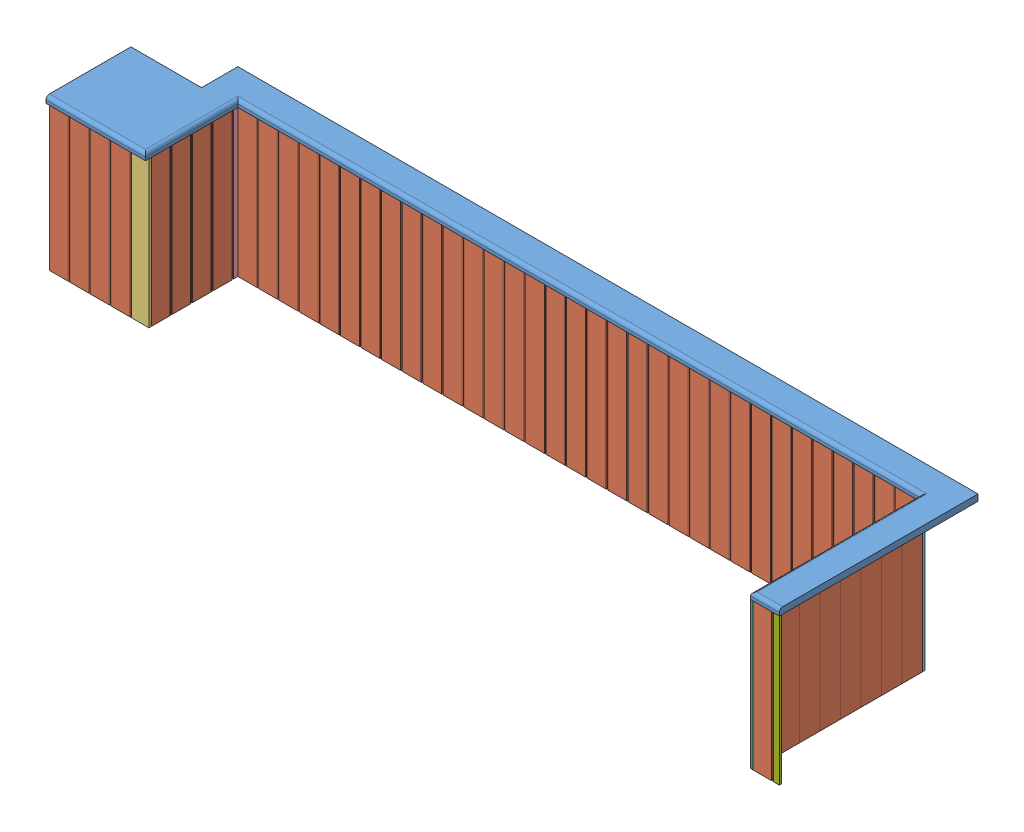
SolidWorks assembly Brüstung, configuration Standard. Lengths in mm.
Overall size (4870 900 1170).
56 component instances, 7 part files, 166 mates.
Components (placement in the parent):
- Platte-1: Platte [Standard] at (1989.1315 795.0064 4189) size (4774 38 1170)
- Wandbrett-1: Wandbrett [Standard] at (-2724.3685 795.0064 4876) x (1 0 0) z (0 0 -1) size (131 862 14)
- Wandbrett-2: Wandbrett [Standard] at (-2603.3685 795.0064 4876) x (1 0 0) z (0 0 -1) size (131 862 14)
- Wandbrett-3: Wandbrett [Standard] at (-2482.3685 795.0064 4876) x (1 0 0) z (0 0 -1) size (131 862 14)
- Wandbrett-4: Wandbrett [Standard] at (-2361.3685 795.0064 4876) x (1 0 0) z (0 0 -1) size (131 862 14)
- Wandbrett-Ecke1-1: Wandbrett-Ecke1 [Standard] at (-2240.3685 795.0064 4876) x (1 0 0) z (0 0 -1) size (102 862 14)
- Wandbrett-6: Wandbrett [Standard] at (-2205.8685 795.0064 4808.5) x (0 0 -1) z (-1 0 0) size (131 862 14)
- Wandbrett-7: Wandbrett [Standard] at (-2205.8685 795.0064 4687.5) x (0 0 -1) z (-1 0 0) size (131 862 14)
- Wandbrett-8: Wandbrett [Standard] at (-2205.8685 795.0064 4566.5) x (0 0 -1) z (-1 0 0) size (131 862 14)
- Wandbrett-9: Wandbrett [Standard] at (-2205.8685 795.0064 4445.5) x (0 0 -1) z (-1 0 0) size (131 862 14)
- Wandbrett-Ecke2-1: Wandbrett-Ecke2 [Standard] at (-2205.8685 795.0064 4324.5) x (0 0 -1) z (-1 0 0) size (60 862 14)
- Wandbrett-11: Wandbrett [Standard] at (-2138.3685 795.0064 4352) x (1 0 0) z (0 0 -1) size (131 862 14)
- Wandbrett-12: Wandbrett [Standard] at (-2017.3685 795.0064 4352) x (1 0 0) z (0 0 -1) size (131 862 14)
- Wandbrett-13: Wandbrett [Standard] at (-1896.3685 795.0064 4352) x (1 0 0) z (0 0 -1) size (131 862 14)
- Wandbrett-14: Wandbrett [Standard] at (-1775.3685 795.0064 4352) x (1 0 0) z (0 0 -1) size (131 862 14)
- Wandbrett-15: Wandbrett [Standard] at (-1654.3685 795.0064 4352) x (1 0 0) z (0 0 -1) size (131 862 14)
- Wandbrett-16: Wandbrett [Standard] at (-1533.3685 795.0064 4352) x (1 0 0) z (0 0 -1) size (131 862 14)
- Wandbrett-17: Wandbrett [Standard] at (-1412.3685 795.0064 4352) x (1 0 0) z (0 0 -1) size (131 862 14)
- Wandbrett-18: Wandbrett [Standard] at (-1291.3685 795.0064 4352) x (1 0 0) z (0 0 -1) size (131 862 14)
- Wandbrett-19: Wandbrett [Standard] at (-1170.3685 795.0064 4352) x (1 0 0) z (0 0 -1) size (131 862 14)
- Wandbrett-20: Wandbrett [Standard] at (-1049.3685 795.0064 4352) x (1 0 0) z (0 0 -1) size (131 862 14)
- Wandbrett-21: Wandbrett [Standard] at (-928.3685 795.0064 4352) x (1 0 0) z (0 0 -1) size (131 862 14)
- Wandbrett-22: Wandbrett [Standard] at (-807.3685 795.0064 4352) x (1 0 0) z (0 0 -1) size (131 862 14)
- Wandbrett-23: Wandbrett [Standard] at (-686.3685 795.0064 4352) x (1 0 0) z (0 0 -1) size (131 862 14)
- Wandbrett-24: Wandbrett [Standard] at (-565.3685 795.0064 4352) x (1 0 0) z (0 0 -1) size (131 862 14)
- Wandbrett-25: Wandbrett [Standard] at (-444.3685 795.0064 4352) x (1 0 0) z (0 0 -1) size (131 862 14)
- Wandbrett-26: Wandbrett [Standard] at (-323.3685 795.0064 4352) x (1 0 0) z (0 0 -1) size (131 862 14)
- Wandbrett-27: Wandbrett [Standard] at (-202.3685 795.0064 4352) x (1 0 0) z (0 0 -1) size (131 862 14)
- Wandbrett-28: Wandbrett [Standard] at (-81.3685 795.0064 4352) x (1 0 0) z (0 0 -1) size (131 862 14)
- Wandbrett-29: Wandbrett [Standard] at (39.6315 795.0064 4352) x (1 0 0) z (0 0 -1) size (131 862 14)
- Wandbrett-30: Wandbrett [Standard] at (160.6315 795.0064 4352) x (1 0 0) z (0 0 -1) size (131 862 14)
- Wandbrett-31: Wandbrett [Standard] at (281.6315 795.0064 4352) x (1 0 0) z (0 0 -1) size (131 862 14)
- Wandbrett-32: Wandbrett [Standard] at (402.6315 795.0064 4352) x (1 0 0) z (0 0 -1) size (131 862 14)
- Wandbrett-33: Wandbrett [Standard] at (523.6315 795.0064 4352) x (1 0 0) z (0 0 -1) size (131 862 14)
- Wandbrett-34: Wandbrett [Standard] at (644.6315 795.0064 4352) x (1 0 0) z (0 0 -1) size (131 862 14)
- Wandbrett-35: Wandbrett [Standard] at (765.6315 795.0064 4352) x (1 0 0) z (0 0 -1) size (131 862 14)
- Wandbrett-36: Wandbrett [Standard] at (886.6315 795.0064 4352) x (1 0 0) z (0 0 -1) size (131 862 14)
- Wandbrett-37: Wandbrett [Standard] at (1007.6315 795.0064 4352) x (1 0 0) z (0 0 -1) size (131 862 14)
- Wandbrett-38: Wandbrett [Standard] at (1128.6315 795.0064 4352) x (1 0 0) z (0 0 -1) size (131 862 14)
- Wandbrett-39: Wandbrett [Standard] at (1249.6315 795.0064 4352) x (1 0 0) z (0 0 -1) size (131 862 14)
- Wandbrett-40: Wandbrett [Standard] at (1370.6315 795.0064 4352) x (1 0 0) z (0 0 -1) size (131 862 14)
- Wandbrett-41: Wandbrett [Standard] at (1491.6315 795.0064 4352) x (1 0 0) z (0 0 -1) size (131 862 14)
- Wandbrett-42: Wandbrett [Standard] at (1612.6315 795.0064 4352) x (1 0 0) z (0 0 -1) size (131 862 14)
- Wandbrett-43: Wandbrett [Standard] at (1733.6315 795.0064 4352) x (1 0 0) z (0 0 -1) size (131 862 14)
- Wandbrett-Ecke3-1: Wandbrett-Ecke3 [Standard] at (1854.6315 795.0064 4352) x (1 0 0) z (0 0 -1) size (39 862 14)
- Wandbrett-44: Wandbrett [Standard] at (1826.1315 795.0064 4419.5) x (0 0 1) z (1 0 0) size (131 862 14)
- Wandbrett-45: Wandbrett [Standard] at (1826.1315 795.0064 4540.5) x (0 0 1) z (1 0 0) size (131 862 14)
- Wandbrett-46: Wandbrett [Standard] at (1826.1315 795.0064 4661.5) x (0 0 1) z (1 0 0) size (131 862 14)
- Wandbrett-47: Wandbrett [Standard] at (1826.1315 795.0064 4782.5) x (0 0 1) z (1 0 0) size (131 862 14)
- Wandbrett-48: Wandbrett [Standard] at (1826.1315 795.0064 4903.5) x (0 0 1) z (1 0 0) size (131 862 14)
- Wandbrett-49: Wandbrett [Standard] at (1826.1315 795.0064 5024.5) x (0 0 1) z (1 0 0) size (131 862 14)
- Wandbrett-50: Wandbrett [Standard] at (1826.1315 795.0064 5145.5) x (0 0 1) z (1 0 0) size (131 862 14)
- Wandbrett-51: Wandbrett [Standard] at (1826.1315 795.0064 5266.5) x (0 0 1) z (1 0 0) size (131 862 14)
- Wandbrett-Ecke4-1: Wandbrett-Ecke4 [Standard] at (1826.1315 795.0064 5387.5) x (0 0 1) z (1 0 0) size (32 862 14)
- Wandbrett-52: Wandbrett [Standard] at (1893.6315 795.0064 5352) x (1 0 0) z (0 0 -1) size (131 862 14)
- Wandbrett-Ecke5-1: Wandbrett-Ecke5 [Standard] at (2014.6315 795.0064 5352) x (1 0 0) z (0 0 -1) size (131 862 14)
Mates (geometry in assembly coordinates):
- Deckungsgleich1: coincident anti-aligned: plane of Platte-1 through (1989.1315 795.0064 4189) normal (0 -1 0); plane of Wandbrett-1 through (-2674.8685 795.0064 4879) normal (0 1 0)
- Deckungsgleich2: coincident anti-aligned: plane of Platte-1 through (1989.1315 795.0064 4189) normal (0 -1 0); plane of Wandbrett-2 through (-2553.8685 795.0064 4879) normal (0 1 0)
- Deckungsgleich3: coincident anti-aligned: plane of Platte-1 through (1989.1315 795.0064 4189) normal (0 -1 0); plane of Wandbrett-3 through (-2432.8685 795.0064 4879) normal (0 1 0)
- Deckungsgleich4: coincident anti-aligned: plane of Platte-1 through (1989.1315 795.0064 4189) normal (0 -1 0); plane of Wandbrett-4 through (-2311.8685 795.0064 4879) normal (0 1 0)
- Parallel1: parallel aligned: plane of Platte-1 through (-2784.8685 833.0064 4903) normal (0 0 1); plane of Wandbrett-1 through (-2674.8685 -66.9936 4883) normal (0 0 1)
- Abstand2: distance = 20 mm aligned: plane of Wandbrett-1 through (-2674.8685 -66.9936 4883) normal (0 0 1); plane of Platte-1 through (-2784.8685 833.0064 4903) normal (0 0 1)
- Deckungsgleich9: coincident aligned: plane of Platte-1 through (-2784.8685 833.0064 4903) normal (-1 0 0); plane of Wandbrett-1 through (-2784.8685 -66.9936 4869) normal (-1 0 0)
- Deckungsgleich10: coincident anti-aligned: plane of Wandbrett-1 through (-2663.8685 -66.9936 4878) normal (0 0 1); plane of Wandbrett-2 through (-2653.8685 -66.9936 4878) normal (0 0 -1)
- Deckungsgleich11: coincident anti-aligned: plane of Wandbrett-2 through (-2542.8685 -66.9936 4878) normal (0 0 1); plane of Wandbrett-3 through (-2532.8685 -66.9936 4878) normal (0 0 -1)
- Deckungsgleich12: coincident anti-aligned: plane of Wandbrett-3 through (-2421.8685 -66.9936 4878) normal (0 0 1); plane of Wandbrett-4 through (-2411.8685 -66.9936 4878) normal (0 0 -1)
- Deckungsgleich14: coincident anti-aligned: plane of Wandbrett-1 through (-2653.8685 -66.9936 4878) normal (1 0 0); plane of Wandbrett-2 through (-2653.8685 -66.9936 4874) normal (-1 0 0)
- Deckungsgleich15: coincident anti-aligned: plane of Wandbrett-2 through (-2532.8685 -66.9936 4878) normal (1 0 0); plane of Wandbrett-3 through (-2532.8685 -66.9936 4874) normal (-1 0 0)
- Deckungsgleich16: coincident anti-aligned: plane of Wandbrett-3 through (-2411.8685 -66.9936 4878) normal (1 0 0); plane of Wandbrett-4 through (-2411.8685 -66.9936 4874) normal (-1 0 0)
- Deckungsgleich18: coincident anti-aligned: plane of Platte-1 through (1989.1315 795.0064 4189) normal (0 -1 0); plane of Wandbrett-Ecke1-1 through (-2190.8685 795.0064 4879) normal (0 1 0)
- Deckungsgleich19: coincident anti-aligned: plane of Wandbrett-4 through (-2300.8685 -66.9936 4878) normal (0 0 1); plane of Wandbrett-Ecke1-1 through (-2290.8685 -66.9936 4878) normal (0 0 -1)
- Deckungsgleich20: coincident anti-aligned: plane of Wandbrett-4 through (-2290.8685 -66.9936 4878) normal (1 0 0); plane of Wandbrett-Ecke1-1 through (-2290.8685 -66.9936 4874) normal (-1 0 0)
- Deckungsgleich21: coincident anti-aligned: plane of Platte-1 through (1989.1315 795.0064 4189) normal (0 -1 0); plane of Wandbrett-6 through (-2202.8685 795.0064 4759) normal (0 1 0)
- Deckungsgleich22: coincident anti-aligned: plane of Platte-1 through (1989.1315 795.0064 4189) normal (0 -1 0); plane of Wandbrett-7 through (-2202.8685 795.0064 4638) normal (0 1 0)
- Deckungsgleich23: coincident anti-aligned: plane of Platte-1 through (1989.1315 795.0064 4189) normal (0 -1 0); plane of Wandbrett-8 through (-2202.8685 795.0064 4517) normal (0 1 0)
- Deckungsgleich24: coincident anti-aligned: plane of Platte-1 through (1989.1315 795.0064 4189) normal (0 -1 0); plane of Wandbrett-9 through (-2202.8685 795.0064 4396) normal (0 1 0)
- Deckungsgleich26: coincident anti-aligned: plane of Wandbrett-Ecke1-1 through (-2179.8685 -66.9936 4869) normal (0 0 -1); plane of Wandbrett-6 through (-2212.8685 -66.9936 4869) normal (0 0 1)
- Deckungsgleich27: coincident aligned: plane of Platte-1 through (-2198.8685 833.0064 4359) normal (1 0 0); plane of Wandbrett-6 through (-2198.8685 -66.9936 4759) normal (1 0 0)
- Deckungsgleich28: coincident anti-aligned: plane of Wandbrett-6 through (-2203.8685 -66.9936 4748) normal (1 0 0); plane of Wandbrett-7 through (-2203.8685 -66.9936 4738) normal (-1 0 0)
- Deckungsgleich29: coincident anti-aligned: plane of Wandbrett-7 through (-2203.8685 -66.9936 4627) normal (1 0 0); plane of Wandbrett-8 through (-2203.8685 -66.9936 4617) normal (-1 0 0)
- Deckungsgleich30: coincident anti-aligned: plane of Wandbrett-8 through (-2203.8685 -66.9936 4506) normal (1 0 0); plane of Wandbrett-9 through (-2203.8685 -66.9936 4496) normal (-1 0 0)
- Deckungsgleich32: coincident anti-aligned: plane of Wandbrett-6 through (-2203.8685 -66.9936 4738) normal (0 0 -1); plane of Wandbrett-7 through (-2207.8685 -66.9936 4738) normal (0 0 1)
- Deckungsgleich33: coincident anti-aligned: plane of Wandbrett-7 through (-2203.8685 -66.9936 4617) normal (0 0 -1); plane of Wandbrett-8 through (-2207.8685 -66.9936 4617) normal (0 0 1)
- Deckungsgleich34: coincident anti-aligned: plane of Wandbrett-8 through (-2203.8685 -66.9936 4496) normal (0 0 -1); plane of Wandbrett-9 through (-2207.8685 -66.9936 4496) normal (0 0 1)
- Deckungsgleich36: coincident anti-aligned: plane of Platte-1 through (1989.1315 795.0064 4189) normal (0 -1 0); plane of Wandbrett-Ecke2-1 through (-2202.8685 795.0064 4275) normal (0 1 0)
- Deckungsgleich37: coincident anti-aligned: plane of Wandbrett-9 through (-2203.8685 -66.9936 4385) normal (1 0 0); plane of Wandbrett-Ecke2-1 through (-2203.8685 -66.9936 4375) normal (-1 0 0)
- Deckungsgleich38: coincident anti-aligned: plane of Wandbrett-9 through (-2203.8685 -66.9936 4375) normal (0 0 -1); plane of Wandbrett-Ecke2-1 through (-2207.8685 -66.9936 4375) normal (0 0 1)
- Deckungsgleich39: coincident anti-aligned: plane of Platte-1 through (1989.1315 795.0064 4189) normal (0 -1 0); plane of Wandbrett-11 through (-2088.8685 795.0064 4355) normal (0 1 0)
- Deckungsgleich40: coincident anti-aligned: plane of Platte-1 through (1989.1315 795.0064 4189) normal (0 -1 0); plane of Wandbrett-12 through (-1967.8685 795.0064 4355) normal (0 1 0)
- Deckungsgleich41: coincident anti-aligned: plane of Platte-1 through (1989.1315 795.0064 4189) normal (0 -1 0); plane of Wandbrett-13 through (-1846.8685 795.0064 4355) normal (0 1 0)
- Deckungsgleich42: coincident anti-aligned: plane of Platte-1 through (1989.1315 795.0064 4189) normal (0 -1 0); plane of Wandbrett-14 through (-1725.8685 795.0064 4355) normal (0 1 0)
- Deckungsgleich43: coincident anti-aligned: plane of Platte-1 through (1989.1315 795.0064 4189) normal (0 -1 0); plane of Wandbrett-15 through (-1604.8685 795.0064 4355) normal (0 1 0)
- Deckungsgleich44: coincident anti-aligned: plane of Platte-1 through (1989.1315 795.0064 4189) normal (0 -1 0); plane of Wandbrett-16 through (-1483.8685 795.0064 4355) normal (0 1 0)
- Deckungsgleich45: coincident anti-aligned: plane of Platte-1 through (1989.1315 795.0064 4189) normal (0 -1 0); plane of Wandbrett-17 through (-1362.8685 795.0064 4355) normal (0 1 0)
- Deckungsgleich46: coincident anti-aligned: plane of Platte-1 through (1989.1315 795.0064 4189) normal (0 -1 0); plane of Wandbrett-18 through (-1241.8685 795.0064 4355) normal (0 1 0)
- Deckungsgleich47: coincident anti-aligned: plane of Platte-1 through (1989.1315 795.0064 4189) normal (0 -1 0); plane of Wandbrett-19 through (-1120.8685 795.0064 4355) normal (0 1 0)
- Deckungsgleich48: coincident anti-aligned: plane of Platte-1 through (1989.1315 795.0064 4189) normal (0 -1 0); plane of Wandbrett-20 through (-999.8685 795.0064 4355) normal (0 1 0)
- Deckungsgleich49: coincident anti-aligned: plane of Platte-1 through (1989.1315 795.0064 4189) normal (0 -1 0); plane of Wandbrett-21 through (-878.8685 795.0064 4355) normal (0 1 0)
- Deckungsgleich50: coincident anti-aligned: plane of Platte-1 through (1989.1315 795.0064 4189) normal (0 -1 0); plane of Wandbrett-22 through (-757.8685 795.0064 4355) normal (0 1 0)
- Deckungsgleich51: coincident anti-aligned: plane of Platte-1 through (1989.1315 795.0064 4189) normal (0 -1 0); plane of Wandbrett-23 through (-636.8685 795.0064 4355) normal (0 1 0)
- Deckungsgleich52: coincident anti-aligned: plane of Platte-1 through (1989.1315 795.0064 4189) normal (0 -1 0); plane of Wandbrett-24 through (-515.8685 795.0064 4355) normal (0 1 0)
- Deckungsgleich53: coincident anti-aligned: plane of Platte-1 through (1989.1315 795.0064 4189) normal (0 -1 0); plane of Wandbrett-25 through (-394.8685 795.0064 4355) normal (0 1 0)
- Deckungsgleich54: coincident anti-aligned: plane of Platte-1 through (1989.1315 795.0064 4189) normal (0 -1 0); plane of Wandbrett-26 through (-273.8685 795.0064 4355) normal (0 1 0)
- Deckungsgleich55: coincident anti-aligned: plane of Platte-1 through (1989.1315 795.0064 4189) normal (0 -1 0); plane of Wandbrett-27 through (-152.8685 795.0064 4355) normal (0 1 0)
- Deckungsgleich56: coincident anti-aligned: plane of Platte-1 through (1989.1315 795.0064 4189) normal (0 -1 0); plane of Wandbrett-28 through (-31.8685 795.0064 4355) normal (0 1 0)
- Deckungsgleich57: coincident anti-aligned: plane of Platte-1 through (1989.1315 795.0064 4189) normal (0 -1 0); plane of Wandbrett-29 through (89.1315 795.0064 4355) normal (0 1 0)
- Deckungsgleich58: coincident anti-aligned: plane of Platte-1 through (1989.1315 795.0064 4189) normal (0 -1 0); plane of Wandbrett-30 through (210.1315 795.0064 4355) normal (0 1 0)
- Deckungsgleich59: coincident anti-aligned: plane of Platte-1 through (1989.1315 795.0064 4189) normal (0 -1 0); plane of Wandbrett-31 through (331.1315 795.0064 4355) normal (0 1 0)
- Deckungsgleich60: coincident anti-aligned: plane of Platte-1 through (1989.1315 795.0064 4189) normal (0 -1 0); plane of Wandbrett-32 through (452.1315 795.0064 4355) normal (0 1 0)
- Deckungsgleich61: coincident anti-aligned: plane of Platte-1 through (1989.1315 795.0064 4189) normal (0 -1 0); plane of Wandbrett-33 through (573.1315 795.0064 4355) normal (0 1 0)
- Deckungsgleich62: coincident anti-aligned: plane of Platte-1 through (1989.1315 795.0064 4189) normal (0 -1 0); plane of Wandbrett-34 through (694.1315 795.0064 4355) normal (0 1 0)
- Deckungsgleich63: coincident anti-aligned: plane of Platte-1 through (1989.1315 795.0064 4189) normal (0 -1 0); plane of Wandbrett-35 through (815.1315 795.0064 4355) normal (0 1 0)
- Deckungsgleich64: coincident anti-aligned: plane of Platte-1 through (1989.1315 795.0064 4189) normal (0 -1 0); plane of Wandbrett-36 through (936.1315 795.0064 4355) normal (0 1 0)
- Deckungsgleich65: coincident anti-aligned: plane of Platte-1 through (1989.1315 795.0064 4189) normal (0 -1 0); plane of Wandbrett-37 through (1057.1315 795.0064 4355) normal (0 1 0)
- Deckungsgleich66: coincident anti-aligned: plane of Platte-1 through (1989.1315 795.0064 4189) normal (0 -1 0); plane of Wandbrett-38 through (1178.1315 795.0064 4355) normal (0 1 0)
- Deckungsgleich67: coincident anti-aligned: plane of Platte-1 through (1989.1315 795.0064 4189) normal (0 -1 0); plane of Wandbrett-39 through (1299.1315 795.0064 4355) normal (0 1 0)
- Deckungsgleich68: coincident anti-aligned: plane of Platte-1 through (1989.1315 795.0064 4189) normal (0 -1 0); plane of Wandbrett-40 through (1420.1315 795.0064 4355) normal (0 1 0)
- Deckungsgleich69: coincident anti-aligned: plane of Platte-1 through (1989.1315 795.0064 4189) normal (0 -1 0); plane of Wandbrett-41 through (1541.1315 795.0064 4355) normal (0 1 0)
- Deckungsgleich70: coincident anti-aligned: plane of Platte-1 through (1989.1315 795.0064 4189) normal (0 -1 0); plane of Wandbrett-42 through (1662.1315 795.0064 4355) normal (0 1 0)
- Deckungsgleich71: coincident anti-aligned: plane of Wandbrett-Ecke2-1 through (-2198.8685 -66.9936 4275) normal (1 0 0); plane of Wandbrett-11 through (-2198.8685 -66.9936 4354) normal (-1 0 0)
- Deckungsgleich72: coincident anti-aligned: plane of Wandbrett-11 through (-2077.8685 -66.9936 4354) normal (0 0 1); plane of Wandbrett-12 through (-2067.8685 -66.9936 4354) normal (0 0 -1)
- Deckungsgleich73: coincident anti-aligned: plane of Wandbrett-12 through (-1956.8685 -66.9936 4354) normal (0 0 1); plane of Wandbrett-13 through (-1946.8685 -66.9936 4354) normal (0 0 -1)
- Deckungsgleich74: coincident anti-aligned: plane of Wandbrett-13 through (-1835.8685 -66.9936 4354) normal (0 0 1); plane of Wandbrett-14 through (-1825.8685 -66.9936 4354) normal (0 0 -1)
- Deckungsgleich75: coincident anti-aligned: plane of Wandbrett-14 through (-1714.8685 -66.9936 4354) normal (0 0 1); plane of Wandbrett-15 through (-1704.8685 -66.9936 4354) normal (0 0 -1)
- Deckungsgleich76: coincident anti-aligned: plane of Wandbrett-15 through (-1593.8685 -66.9936 4354) normal (0 0 1); plane of Wandbrett-16 through (-1583.8685 -66.9936 4354) normal (0 0 -1)
- Deckungsgleich77: coincident anti-aligned: plane of Wandbrett-16 through (-1472.8685 -66.9936 4354) normal (0 0 1); plane of Wandbrett-17 through (-1462.8685 -66.9936 4354) normal (0 0 -1)
- Deckungsgleich78: coincident anti-aligned: plane of Wandbrett-17 through (-1351.8685 -66.9936 4354) normal (0 0 1); plane of Wandbrett-18 through (-1341.8685 -66.9936 4354) normal (0 0 -1)
- Deckungsgleich79: coincident anti-aligned: plane of Wandbrett-18 through (-1230.8685 -66.9936 4354) normal (0 0 1); plane of Wandbrett-19 through (-1220.8685 -66.9936 4354) normal (0 0 -1)
- Deckungsgleich80: coincident anti-aligned: plane of Wandbrett-19 through (-1109.8685 -66.9936 4354) normal (0 0 1); plane of Wandbrett-20 through (-1099.8685 -66.9936 4354) normal (0 0 -1)
- Deckungsgleich81: coincident anti-aligned: plane of Wandbrett-20 through (-988.8685 -66.9936 4354) normal (0 0 1); plane of Wandbrett-21 through (-978.8685 -66.9936 4354) normal (0 0 -1)
- Deckungsgleich82: coincident anti-aligned: plane of Wandbrett-21 through (-867.8685 -66.9936 4354) normal (0 0 1); plane of Wandbrett-22 through (-857.8685 -66.9936 4354) normal (0 0 -1)
- Deckungsgleich83: coincident anti-aligned: plane of Wandbrett-22 through (-746.8685 -66.9936 4354) normal (0 0 1); plane of Wandbrett-23 through (-736.8685 -66.9936 4354) normal (0 0 -1)
- Deckungsgleich84: coincident anti-aligned: plane of Wandbrett-23 through (-625.8685 -66.9936 4354) normal (0 0 1); plane of Wandbrett-24 through (-615.8685 -66.9936 4354) normal (0 0 -1)
- Deckungsgleich85: coincident anti-aligned: plane of Wandbrett-24 through (-504.8685 -66.9936 4354) normal (0 0 1); plane of Wandbrett-25 through (-494.8685 -66.9936 4354) normal (0 0 -1)
- Deckungsgleich86: coincident anti-aligned: plane of Wandbrett-25 through (-383.8685 -66.9936 4354) normal (0 0 1); plane of Wandbrett-26 through (-373.8685 -66.9936 4354) normal (0 0 -1)
- Deckungsgleich87: coincident anti-aligned: plane of Wandbrett-26 through (-262.8685 -66.9936 4354) normal (0 0 1); plane of Wandbrett-27 through (-252.8685 -66.9936 4354) normal (0 0 -1)
- Deckungsgleich88: coincident anti-aligned: plane of Wandbrett-27 through (-141.8685 -66.9936 4354) normal (0 0 1); plane of Wandbrett-28 through (-131.8685 -66.9936 4354) normal (0 0 -1)
- Deckungsgleich90: coincident anti-aligned: plane of Wandbrett-28 through (-20.8685 -66.9936 4354) normal (0 0 1); plane of Wandbrett-29 through (-10.8685 -66.9936 4354) normal (0 0 -1)
- Deckungsgleich91: coincident anti-aligned: plane of Wandbrett-29 through (100.1315 -66.9936 4354) normal (0 0 1); plane of Wandbrett-30 through (110.1315 -66.9936 4354) normal (0 0 -1)
- Deckungsgleich92: coincident anti-aligned: plane of Wandbrett-30 through (221.1315 -66.9936 4354) normal (0 0 1); plane of Wandbrett-31 through (231.1315 -66.9936 4354) normal (0 0 -1)
- Deckungsgleich93: coincident anti-aligned: plane of Wandbrett-31 through (342.1315 -66.9936 4354) normal (0 0 1); plane of Wandbrett-32 through (352.1315 -66.9936 4354) normal (0 0 -1)
- Deckungsgleich94: coincident anti-aligned: plane of Wandbrett-32 through (463.1315 -66.9936 4354) normal (0 0 1); plane of Wandbrett-33 through (473.1315 -66.9936 4354) normal (0 0 -1)
- Deckungsgleich95: coincident anti-aligned: plane of Wandbrett-33 through (584.1315 -66.9936 4354) normal (0 0 1); plane of Wandbrett-34 through (594.1315 -66.9936 4354) normal (0 0 -1)
- Deckungsgleich96: coincident anti-aligned: plane of Wandbrett-34 through (705.1315 -66.9936 4354) normal (0 0 1); plane of Wandbrett-35 through (715.1315 -66.9936 4354) normal (0 0 -1)
- Deckungsgleich97: coincident anti-aligned: plane of Wandbrett-35 through (826.1315 -66.9936 4354) normal (0 0 1); plane of Wandbrett-36 through (836.1315 -66.9936 4354) normal (0 0 -1)
- Deckungsgleich98: coincident anti-aligned: plane of Wandbrett-36 through (947.1315 -66.9936 4354) normal (0 0 1); plane of Wandbrett-37 through (957.1315 -66.9936 4354) normal (0 0 -1)
- Deckungsgleich99: coincident anti-aligned: plane of Wandbrett-37 through (1068.1315 -66.9936 4354) normal (0 0 1); plane of Wandbrett-38 through (1078.1315 -66.9936 4354) normal (0 0 -1)
- Deckungsgleich100: coincident anti-aligned: plane of Wandbrett-38 through (1189.1315 -66.9936 4354) normal (0 0 1); plane of Wandbrett-39 through (1199.1315 -66.9936 4354) normal (0 0 -1)
- Deckungsgleich101: coincident anti-aligned: plane of Wandbrett-39 through (1310.1315 -66.9936 4354) normal (0 0 1); plane of Wandbrett-40 through (1320.1315 -66.9936 4354) normal (0 0 -1)
- Deckungsgleich102: coincident anti-aligned: plane of Wandbrett-40 through (1431.1315 -66.9936 4354) normal (0 0 1); plane of Wandbrett-41 through (1441.1315 -66.9936 4354) normal (0 0 -1)
- Deckungsgleich103: coincident anti-aligned: plane of Wandbrett-41 through (1552.1315 -66.9936 4354) normal (0 0 1); plane of Wandbrett-42 through (1562.1315 -66.9936 4354) normal (0 0 -1)
- Deckungsgleich104: coincident aligned: plane of Platte-1 through (-2198.8685 833.0064 4359) normal (0 0 1); plane of Wandbrett-11 through (-2088.8685 -66.9936 4359) normal (0 0 1)
- Deckungsgleich105: coincident anti-aligned: plane of Wandbrett-11 through (-2067.8685 -66.9936 4354) normal (1 0 0); plane of Wandbrett-12 through (-2067.8685 -66.9936 4350) normal (-1 0 0)
- Deckungsgleich106: coincident anti-aligned: plane of Wandbrett-12 through (-1946.8685 -66.9936 4354) normal (1 0 0); plane of Wandbrett-13 through (-1946.8685 -66.9936 4350) normal (-1 0 0)
- Deckungsgleich107: coincident anti-aligned: plane of Wandbrett-13 through (-1825.8685 -66.9936 4354) normal (1 0 0); plane of Wandbrett-14 through (-1825.8685 -66.9936 4350) normal (-1 0 0)
- Deckungsgleich108: coincident anti-aligned: plane of Wandbrett-14 through (-1704.8685 -66.9936 4354) normal (1 0 0); plane of Wandbrett-15 through (-1704.8685 -66.9936 4350) normal (-1 0 0)
- Deckungsgleich109: coincident anti-aligned: plane of Wandbrett-15 through (-1583.8685 -66.9936 4354) normal (1 0 0); plane of Wandbrett-16 through (-1583.8685 -66.9936 4350) normal (-1 0 0)
- Deckungsgleich110: coincident anti-aligned: plane of Wandbrett-16 through (-1462.8685 -66.9936 4354) normal (1 0 0); plane of Wandbrett-17 through (-1462.8685 -66.9936 4350) normal (-1 0 0)
- Deckungsgleich111: coincident anti-aligned: plane of Wandbrett-17 through (-1341.8685 -66.9936 4354) normal (1 0 0); plane of Wandbrett-18 through (-1341.8685 -66.9936 4350) normal (-1 0 0)
- Deckungsgleich112: coincident anti-aligned: plane of Wandbrett-18 through (-1220.8685 -66.9936 4354) normal (1 0 0); plane of Wandbrett-19 through (-1220.8685 -66.9936 4350) normal (-1 0 0)
- Deckungsgleich113: coincident anti-aligned: plane of Wandbrett-19 through (-1099.8685 -66.9936 4354) normal (1 0 0); plane of Wandbrett-20 through (-1099.8685 -66.9936 4350) normal (-1 0 0)
- Deckungsgleich114: coincident anti-aligned: plane of Wandbrett-20 through (-978.8685 -66.9936 4354) normal (1 0 0); plane of Wandbrett-21 through (-978.8685 -66.9936 4350) normal (-1 0 0)
- Deckungsgleich115: coincident anti-aligned: plane of Wandbrett-21 through (-857.8685 -66.9936 4354) normal (1 0 0); plane of Wandbrett-22 through (-857.8685 -66.9936 4350) normal (-1 0 0)
- Deckungsgleich117: coincident anti-aligned: plane of Wandbrett-22 through (-736.8685 -66.9936 4354) normal (1 0 0); plane of Wandbrett-23 through (-736.8685 -66.9936 4350) normal (-1 0 0)
- Deckungsgleich118: coincident anti-aligned: plane of Wandbrett-23 through (-615.8685 -66.9936 4354) normal (1 0 0); plane of Wandbrett-24 through (-615.8685 -66.9936 4350) normal (-1 0 0)
- Deckungsgleich119: coincident anti-aligned: plane of Wandbrett-24 through (-494.8685 -66.9936 4354) normal (1 0 0); plane of Wandbrett-25 through (-494.8685 -66.9936 4350) normal (-1 0 0)
- Deckungsgleich121: coincident anti-aligned: plane of Wandbrett-25 through (-373.8685 -66.9936 4354) normal (1 0 0); plane of Wandbrett-26 through (-373.8685 -66.9936 4350) normal (-1 0 0)
- Deckungsgleich122: coincident anti-aligned: plane of Wandbrett-26 through (-252.8685 -66.9936 4354) normal (1 0 0); plane of Wandbrett-27 through (-252.8685 -66.9936 4350) normal (-1 0 0)
- Deckungsgleich123: coincident anti-aligned: plane of Wandbrett-27 through (-131.8685 -66.9936 4354) normal (1 0 0); plane of Wandbrett-28 through (-131.8685 -66.9936 4350) normal (-1 0 0)
- Deckungsgleich124: coincident anti-aligned: plane of Wandbrett-28 through (-10.8685 -66.9936 4354) normal (1 0 0); plane of Wandbrett-29 through (-10.8685 -66.9936 4350) normal (-1 0 0)
- Deckungsgleich125: coincident anti-aligned: plane of Wandbrett-29 through (110.1315 -66.9936 4354) normal (1 0 0); plane of Wandbrett-30 through (110.1315 -66.9936 4350) normal (-1 0 0)
- Deckungsgleich126: coincident anti-aligned: plane of Wandbrett-30 through (231.1315 -66.9936 4354) normal (1 0 0); plane of Wandbrett-31 through (231.1315 -66.9936 4350) normal (-1 0 0)
- Deckungsgleich127: coincident anti-aligned: plane of Wandbrett-31 through (352.1315 -66.9936 4354) normal (1 0 0); plane of Wandbrett-32 through (352.1315 -66.9936 4350) normal (-1 0 0)
- Deckungsgleich128: coincident anti-aligned: plane of Wandbrett-32 through (473.1315 -66.9936 4354) normal (1 0 0); plane of Wandbrett-33 through (473.1315 -66.9936 4350) normal (-1 0 0)
- Deckungsgleich129: coincident anti-aligned: plane of Wandbrett-33 through (594.1315 -66.9936 4354) normal (1 0 0); plane of Wandbrett-34 through (594.1315 -66.9936 4350) normal (-1 0 0)
- Deckungsgleich130: coincident anti-aligned: plane of Wandbrett-34 through (715.1315 -66.9936 4354) normal (1 0 0); plane of Wandbrett-35 through (715.1315 -66.9936 4350) normal (-1 0 0)
- Deckungsgleich131: coincident anti-aligned: plane of Wandbrett-35 through (836.1315 -66.9936 4354) normal (1 0 0); plane of Wandbrett-36 through (836.1315 -66.9936 4350) normal (-1 0 0)
- Deckungsgleich132: coincident anti-aligned: plane of Wandbrett-36 through (957.1315 -66.9936 4354) normal (1 0 0); plane of Wandbrett-37 through (957.1315 -66.9936 4350) normal (-1 0 0)
- Deckungsgleich133: coincident anti-aligned: plane of Wandbrett-37 through (1078.1315 -66.9936 4354) normal (1 0 0); plane of Wandbrett-38 through (1078.1315 -66.9936 4350) normal (-1 0 0)
- Deckungsgleich136: coincident anti-aligned: plane of Wandbrett-38 through (1199.1315 -66.9936 4354) normal (1 0 0); plane of Wandbrett-39 through (1199.1315 -66.9936 4350) normal (-1 0 0)
- Deckungsgleich137: coincident anti-aligned: plane of Wandbrett-39 through (1320.1315 -66.9936 4354) normal (1 0 0); plane of Wandbrett-40 through (1320.1315 -66.9936 4350) normal (-1 0 0)
- Deckungsgleich138: coincident anti-aligned: plane of Wandbrett-40 through (1441.1315 -66.9936 4354) normal (1 0 0); plane of Wandbrett-41 through (1441.1315 -66.9936 4350) normal (-1 0 0)
- Deckungsgleich139: coincident anti-aligned: plane of Wandbrett-41 through (1562.1315 -66.9936 4354) normal (1 0 0); plane of Wandbrett-42 through (1562.1315 -66.9936 4350) normal (-1 0 0)
- Deckungsgleich140: coincident anti-aligned: plane of Platte-1 through (1989.1315 795.0064 4189) normal (0 -1 0); plane of Wandbrett-43 through (1783.1315 795.0064 4355) normal (0 1 0)
- Deckungsgleich141: coincident anti-aligned: plane of Wandbrett-42 through (1673.1315 -66.9936 4354) normal (0 0 1); plane of Wandbrett-43 through (1683.1315 -66.9936 4354) normal (0 0 -1)
- Deckungsgleich142: coincident anti-aligned: plane of Wandbrett-42 through (1683.1315 -66.9936 4354) normal (1 0 0); plane of Wandbrett-43 through (1683.1315 -66.9936 4350) normal (-1 0 0)
- Deckungsgleich143: coincident anti-aligned: plane of Platte-1 through (1989.1315 795.0064 4189) normal (0 -1 0); plane of Wandbrett-Ecke3-1 through (1904.1315 795.0064 4355) normal (0 1 0)
- Deckungsgleich144: coincident anti-aligned: plane of Wandbrett-43 through (1794.1315 -66.9936 4354) normal (0 0 1); plane of Wandbrett-Ecke3-1 through (1804.1315 -66.9936 4354) normal (0 0 -1)
- Deckungsgleich145: coincident anti-aligned: plane of Wandbrett-43 through (1804.1315 -66.9936 4354) normal (1 0 0); plane of Wandbrett-Ecke3-1 through (1804.1315 -66.9936 4350) normal (-1 0 0)
- Deckungsgleich156: coincident anti-aligned: plane of Platte-1 through (1989.1315 795.0064 4189) normal (0 -1 0); plane of Wandbrett-44 through (1823.1315 795.0064 4469) normal (0 1 0)
- Deckungsgleich157: coincident anti-aligned: plane of Platte-1 through (1989.1315 795.0064 4189) normal (0 -1 0); plane of Wandbrett-45 through (1823.1315 795.0064 4590) normal (0 1 0)
- Deckungsgleich158: coincident anti-aligned: plane of Platte-1 through (1989.1315 795.0064 4189) normal (0 -1 0); plane of Wandbrett-46 through (1823.1315 795.0064 4711) normal (0 1 0)
- Deckungsgleich159: coincident anti-aligned: plane of Platte-1 through (1989.1315 795.0064 4189) normal (0 -1 0); plane of Wandbrett-47 through (1823.1315 795.0064 4832) normal (0 1 0)
- Deckungsgleich160: coincident anti-aligned: plane of Platte-1 through (1989.1315 795.0064 4189) normal (0 -1 0); plane of Wandbrett-48 through (1823.1315 795.0064 4953) normal (0 1 0)
- Deckungsgleich161: coincident anti-aligned: plane of Platte-1 through (1989.1315 795.0064 4189) normal (0 -1 0); plane of Wandbrett-49 through (1823.1315 795.0064 5074) normal (0 1 0)
- Deckungsgleich162: coincident anti-aligned: plane of Platte-1 through (1989.1315 795.0064 4189) normal (0 -1 0); plane of Wandbrett-50 through (1823.1315 795.0064 5195) normal (0 1 0)
- Deckungsgleich163: coincident anti-aligned: plane of Platte-1 through (1989.1315 795.0064 4189) normal (0 -1 0); plane of Wandbrett-51 through (1823.1315 795.0064 5316) normal (0 1 0)
- Deckungsgleich164: coincident anti-aligned: plane of Wandbrett-Ecke3-1 through (1904.1315 -66.9936 4359) normal (0 0 1); plane of Wandbrett-44 through (1824.1315 -66.9936 4359) normal (0 0 -1)
- Deckungsgleich165: coincident aligned: plane of Platte-1 through (1819.1315 833.0064 4359) normal (-1 0 0); plane of Wandbrett-44 through (1819.1315 -66.9936 4469) normal (-1 0 0)
- Deckungsgleich166: coincident anti-aligned: plane of Wandbrett-44 through (1824.1315 -66.9936 4480) normal (-1 0 0); plane of Wandbrett-45 through (1824.1315 -66.9936 4490) normal (1 0 0)
- Deckungsgleich167: coincident anti-aligned: plane of Wandbrett-45 through (1824.1315 -66.9936 4601) normal (-1 0 0); plane of Wandbrett-46 through (1824.1315 -66.9936 4611) normal (1 0 0)
- Deckungsgleich168: coincident anti-aligned: plane of Wandbrett-46 through (1824.1315 -66.9936 4722) normal (-1 0 0); plane of Wandbrett-47 through (1824.1315 -66.9936 4732) normal (1 0 0)
- Deckungsgleich169: coincident anti-aligned: plane of Wandbrett-47 through (1824.1315 -66.9936 4843) normal (-1 0 0); plane of Wandbrett-48 through (1824.1315 -66.9936 4853) normal (1 0 0)
- Deckungsgleich170: coincident anti-aligned: plane of Wandbrett-48 through (1824.1315 -66.9936 4964) normal (-1 0 0); plane of Wandbrett-49 through (1824.1315 -66.9936 4974) normal (1 0 0)
- Deckungsgleich171: coincident anti-aligned: plane of Wandbrett-49 through (1824.1315 -66.9936 5085) normal (-1 0 0); plane of Wandbrett-50 through (1824.1315 -66.9936 5095) normal (1 0 0)
- Deckungsgleich172: coincident anti-aligned: plane of Wandbrett-50 through (1824.1315 -66.9936 5206) normal (-1 0 0); plane of Wandbrett-51 through (1824.1315 -66.9936 5216) normal (1 0 0)
- Deckungsgleich173: coincident anti-aligned: plane of Wandbrett-44 through (1824.1315 -66.9936 4490) normal (0 0 1); plane of Wandbrett-45 through (1828.1315 -66.9936 4490) normal (0 0 -1)
- Deckungsgleich174: coincident anti-aligned: plane of Wandbrett-45 through (1824.1315 -66.9936 4611) normal (0 0 1); plane of Wandbrett-46 through (1828.1315 -66.9936 4611) normal (0 0 -1)
- Deckungsgleich175: coincident anti-aligned: plane of Wandbrett-46 through (1824.1315 -66.9936 4732) normal (0 0 1); plane of Wandbrett-47 through (1828.1315 -66.9936 4732) normal (0 0 -1)
- Deckungsgleich176: coincident anti-aligned: plane of Wandbrett-47 through (1824.1315 -66.9936 4853) normal (0 0 1); plane of Wandbrett-48 through (1828.1315 -66.9936 4853) normal (0 0 -1)
- Deckungsgleich177: coincident anti-aligned: plane of Wandbrett-48 through (1824.1315 -66.9936 4974) normal (0 0 1); plane of Wandbrett-49 through (1828.1315 -66.9936 4974) normal (0 0 -1)
- Deckungsgleich179: coincident anti-aligned: plane of Wandbrett-49 through (1824.1315 -66.9936 5095) normal (0 0 1); plane of Wandbrett-50 through (1828.1315 -66.9936 5095) normal (0 0 -1)
- Deckungsgleich180: coincident anti-aligned: plane of Wandbrett-50 through (1824.1315 -66.9936 5216) normal (0 0 1); plane of Wandbrett-51 through (1828.1315 -66.9936 5216) normal (0 0 -1)
- Deckungsgleich181: coincident anti-aligned: plane of Platte-1 through (1989.1315 795.0064 4189) normal (0 -1 0); plane of Wandbrett-Ecke4-1 through (1823.1315 795.0064 5437) normal (0 1 0)
- Deckungsgleich182: coincident anti-aligned: plane of Wandbrett-51 through (1824.1315 -66.9936 5327) normal (-1 0 0); plane of Wandbrett-Ecke4-1 through (1824.1315 -66.9936 5337) normal (1 0 0)
- Deckungsgleich183: coincident anti-aligned: plane of Wandbrett-51 through (1824.1315 -66.9936 5337) normal (0 0 1); plane of Wandbrett-Ecke4-1 through (1828.1315 -66.9936 5337) normal (0 0 -1)
- Deckungsgleich184: coincident anti-aligned: plane of Platte-1 through (1989.1315 795.0064 4189) normal (0 -1 0); plane of Wandbrett-52 through (1943.1315 795.0064 5355) normal (0 1 0)
- Deckungsgleich185: coincident anti-aligned: plane of Wandbrett-Ecke4-1 through (1833.1315 -66.9936 5448) normal (1 0 0); plane of Wandbrett-52 through (1833.1315 -66.9936 5354) normal (-1 0 0)
- Deckungsgleich186: coincident aligned: plane of Platte-1 through (1989.1315 833.0064 5359) normal (0 0 1); plane of Wandbrett-52 through (1943.1315 -66.9936 5359) normal (0 0 1)
- Deckungsgleich187: coincident anti-aligned: plane of Platte-1 through (1989.1315 795.0064 4189) normal (0 -1 0); plane of Wandbrett-Ecke5-1 through (2064.1315 795.0064 5355) normal (0 1 0)
- Deckungsgleich188: coincident anti-aligned: plane of Wandbrett-52 through (1964.1315 -66.9936 5354) normal (1 0 0); plane of Wandbrett-Ecke5-1 through (1964.1315 -66.9936 5350) normal (-1 0 0)
- Deckungsgleich189: coincident anti-aligned: plane of Wandbrett-52 through (1954.1315 -66.9936 5354) normal (0 0 1); plane of Wandbrett-Ecke5-1 through (1964.1315 -66.9936 5354) normal (0 0 -1)
